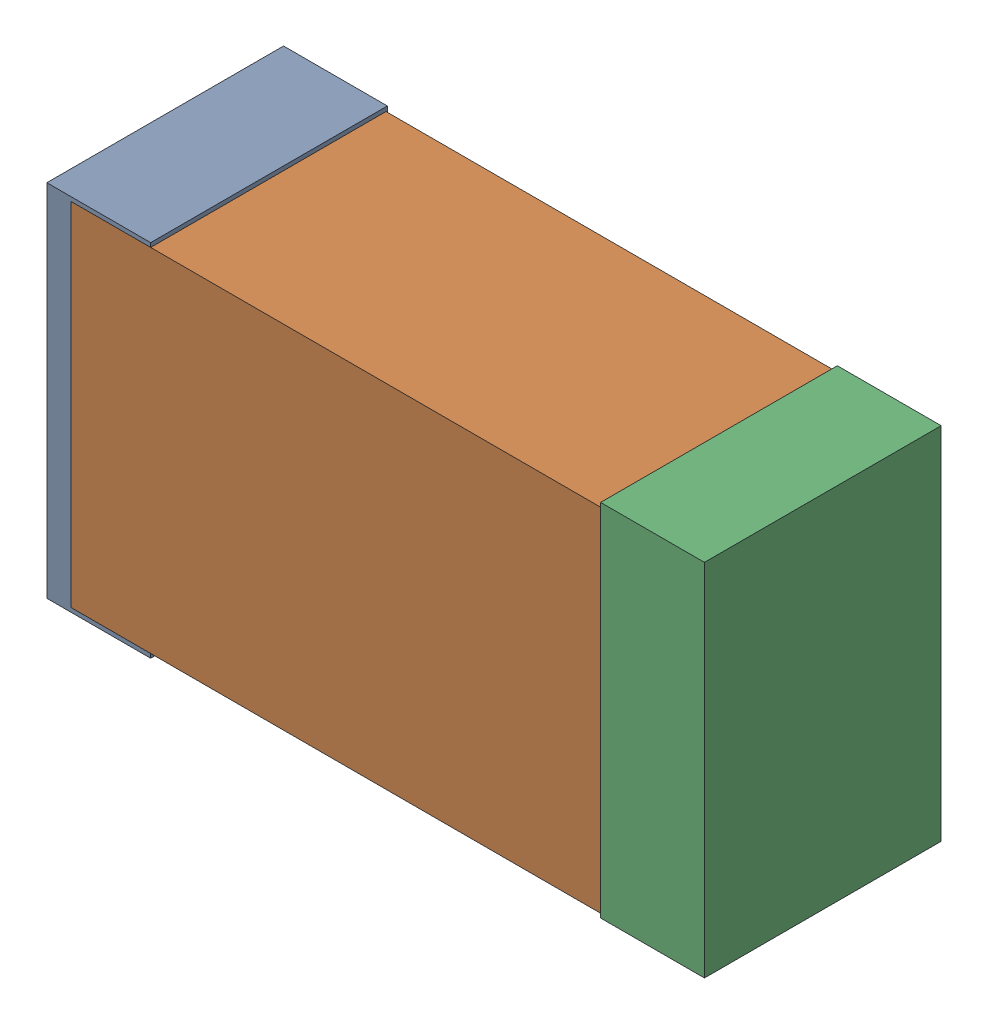
SolidWorks assembly USB23_C11, configuration Default. Lengths in mm.
Overall size (2.38 1.3 0.85).
6 component instances, 2 part files, 0 mates.
Components (placement in the parent):
- 384311232-1: 384311232 [Default] at (172.99 55.499 -1.9574) size (0.38 1.3 0.85)
  - Extruded_8-1: Extruded_8 [Default] at origin size (0.38 1.3 0.85)
- 402662800-1: 402662800 [Default] at (173.99 55.499 -1.9524) size (2.2 1.27 0.85)
  - Extruded_30-1: Extruded_30 [Default] at origin size (2.2 1.27 0.85)
- 384311232-2: 384311232 [Default] at (174.99 55.499 -1.9574) size (0.38 1.3 0.85)
  - Extruded_8-1: Extruded_8 [Default] at origin size (0.38 1.3 0.85)
